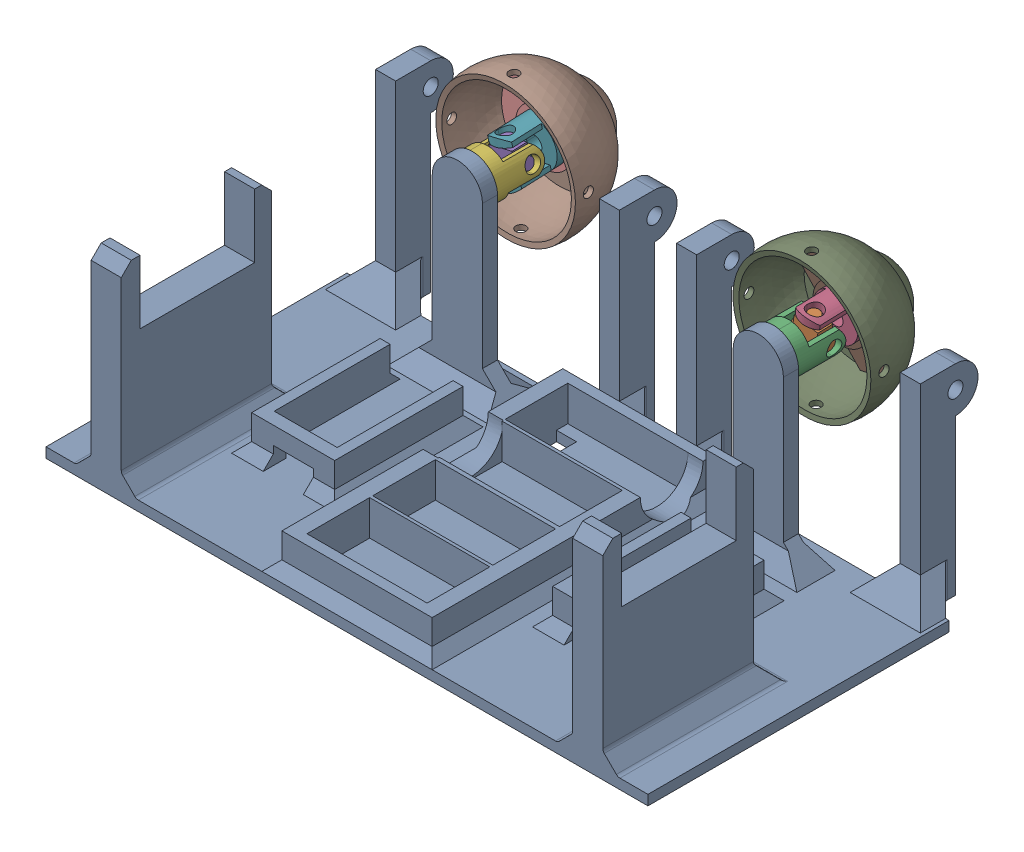
SolidWorks assembly EyeAssemblyFinal2, configuration Default. Lengths in mm.
Overall size (120 50.29 79.98).
13 component instances, 5 part files, 17 mates.
Components (placement in the parent):
- BASE_v3_pasha-4: BASE_v3_pasha [Default] at origin size (120 40.7 71.5)
- UV_Final-4: UV_Final [Default] at (29.2298 41.5773 -36.6858) x (0.986642 -0.162905 0) z (-0.162819 -0.986118 -0.032589) size (9.05 15.57 9.32) (hidden)
  - UV cross spider[1].step-1: UV cross spider[1].step [Default] at (1.7499 4.175 5.7377) size (7.2 3 7.2)
  - UV Yoke[1].step-1: UV Yoke[1].step [Default] at (1.7499 11.8709 5.4867) x (1 0 0) z (0 -0.032589 -0.999469) size (9.01 10 9)
  - UV Yoke[1].step-2: UV Yoke[1].step [Default] at (1.7085 -3.5249 5.7377) x (0 0 -1) z (0.999986 -0.005381 0) size (9.01 10 9)
- UV_Final-5: UV_Final [Default] at (-33.0686 40.802 -36.6858) x (0.972522 0.232812 0) z (0.232689 -0.972005 -0.032589) size (9.05 15.57 9.32)
  - UV cross spider[1].step-1: UV cross spider[1].step [Default] at (1.7499 4.175 5.7377) size (7.2 3 7.2)
  - UV Yoke[1].step-1: UV Yoke[1].step [Default] at (1.7499 11.8709 5.4867) x (1 0 0) z (0 -0.032589 -0.999469) size (9.01 10 9)
  - UV Yoke[1].step-2: UV Yoke[1].step [Default] at (1.7085 -3.5249 5.7377) x (0 0 -1) z (0.999986 -0.005381 0) size (9.01 10 9)
- eye ball-3: eye ball [Default] at (-30.0207 35.549 -34.3103) x (0.01282 -0.03044 0.999454) z (-0.999706 -0.020948 0.012185) size (17.77 28 28)
- eye ball-4: eye ball [Default] at (30 35.5231 -33.3996) x (0 -0.033029 0.999454) z (-1 0 0) size (17.77 28 28) (hidden)
- UVHOLDERSLDPART-3: UVHOLDERSLDPART [Default] at (-30.1104 35.7621 -41.3065) x (-0.999918 -0.000328 0.012816) z (-0.01282 0.03044 -0.999454) size (20.5 15.75 3)
- UVHOLDERSLDPART-4: UVHOLDERSLDPART [Default] at (30 35.7543 -40.3958) x (-0.659749 0.751076 0.024821) z (0 0.033029 -0.999454) size (20.5 15.75 3)
Mates (geometry in assembly coordinates):
- Coincident7: coordinate: point of BASE_v3_pasha-4
- Coincident9: coordinate: unknown of BASE_v3_pasha-4
- Concentric1: concentric aligned: cylinder of BASE_v3_pasha-4 through (30 35.5 -30) axis (0 0 1) radius 1.5; cylinder of UV_Final-4/UV Yoke[1].step-1 through (30 35.5 -28) axis (0 0 1) radius 1.5
- Concentric2: concentric aligned: cylinder of BASE_v3_pasha-4 through (30 35.5 -30) axis (0 0 1) radius 1.5; cylinder of UV_Final-4/UV Yoke[1].step-1 through (30 35.5 -28) axis (0 0 1) radius 1.5
- Coincident10: coincident anti-aligned: plane of BASE_v3_pasha-4 through (35 35.5 -25) normal (0 0 -1); plane of UV_Final-4/UV Yoke[1].step-1 through (30 35.5 -25) normal (0 0 1)
- Concentric3: concentric aligned: cylinder of BASE_v3_pasha-4 through (-30 35.5 -30) axis (0 0 1) radius 1.5; cylinder of UV_Final-5/UV Yoke[1].step-1 through (-30 35.5 -28) axis (0 0 1) radius 1.5
- Concentric4: concentric aligned: cylinder of BASE_v3_pasha-4 through (-30 35.5 -30) axis (0 0 1) radius 1.5; cylinder of UV_Final-5/UV Yoke[1].step-1 through (-30 35.5 -28) axis (0 0 1) radius 1.5
- Concentric5: concentric aligned: cylinder of BASE_v3_pasha-4 through (-30 35.5 -30) axis (0 0 1) radius 1.5; cylinder of UV_Final-5/UV Yoke[1].step-1 through (-30 35.5 -28) axis (0 0 1) radius 1.5
- Coincident11: coincident anti-aligned: plane of BASE_v3_pasha-4 through (-35 35.5 -25) normal (0 0 -1); plane of UV_Final-5/UV Yoke[1].step-1 through (-30 35.5 -25) normal (0 0 1)
- Concentric12: concentric aligned: cylinder of UV_Final-5/UV Yoke[1].step-2 through (-30.0603 35.6431 -37.3974) axis (-0.01282 0.03044 -0.999454) radius 4.5; cylinder of UVHOLDERSLDPART-3 through (-30.0848 35.7012 -39.3076) axis (-0.01282 0.03044 -0.999454) radius 4.5
- Concentric13: concentric aligned: cylinder of UV_Final-4/UV Yoke[1].step-2 through (30 35.6552 -37.3974) axis (0 0.033029 -0.999454) radius 4.5; cylinder of UVHOLDERSLDPART-4 through (30 35.6883 -38.3969) axis (0 0.033029 -0.999454) radius 4.5
- Coincident27: coincident anti-aligned: plane of UV_Final-4/UV Yoke[1].step-2 through (30 35.7543 -40.3958) normal (0 0.033029 -0.999454); plane of UVHOLDERSLDPART-4 through (30 35.7543 -40.3958) normal (0 -0.033029 0.999454)
- Concentric14: concentric aligned: circle of eye ball-3; circle of UVHOLDERSLDPART-3
- Concentric15: concentric aligned: circle of eye ball-4; circle of UVHOLDERSLDPART-4
- Coincident28: coincident anti-aligned: plane of eye ball-3 through (-30.1232 35.7926 -42.3059) normal (0.01282 -0.03044 0.999454); plane of UVHOLDERSLDPART-3 through (-30.1232 35.7926 -42.3059) normal (-0.01282 0.03044 -0.999454)
- Coincident29: coincident anti-aligned: plane of eye ball-4 through (30 35.7874 -41.3953) normal (0 -0.033029 0.999454); plane of UVHOLDERSLDPART-4 through (30 35.7874 -41.3953) normal (0 0.033029 -0.999454)
- Parallel1: parallel aligned: cylinder of BASE_v3_pasha-4 through (67.0279 35.5 -37) axis (-1 0 0) radius 1.5; cylinder of eye ball-4 through (44 35.5132 -33.0982) axis (-1 0 0) radius 1
